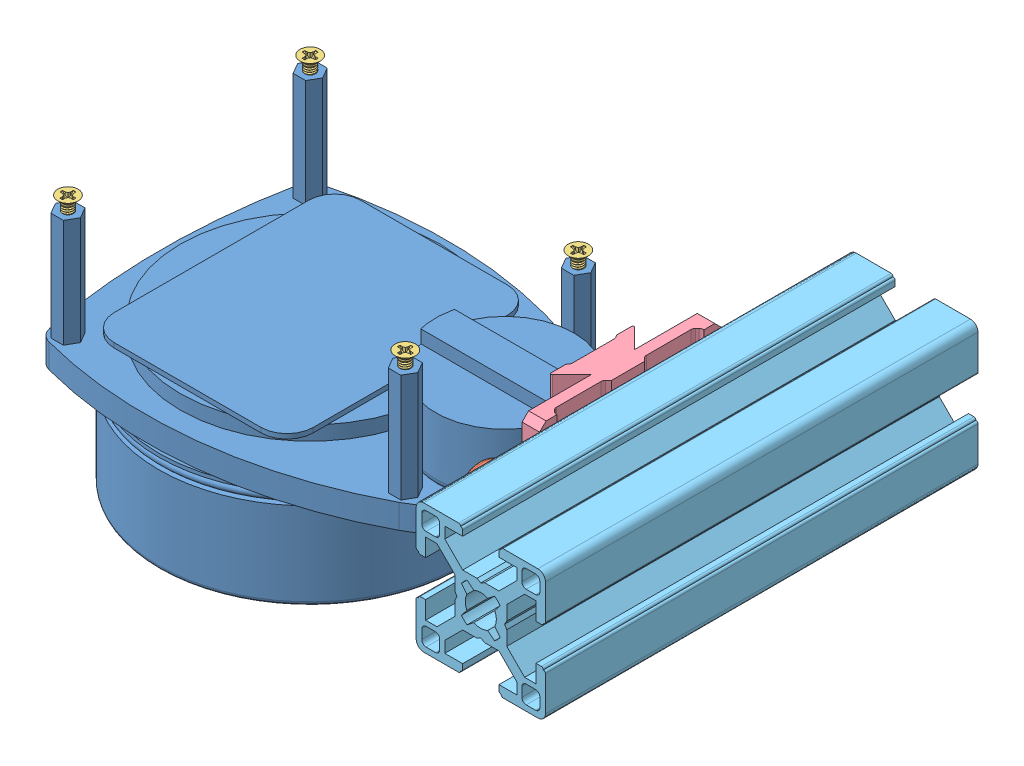
SolidWorks assembly LidarDoveTail, configuration Default. Lengths in mm.
Overall size (139.4 59.25 70).
10 component instances, 6 part files, 31 mates.
Components (placement in the parent):
- RPLidar_SCTL-1: RPLidar_SCTL [Default] at (-64 -20.75 0) x (1 0 0) z (0 0 -1) size (96.17 54.6 70)
- lidarBrack-1: lidarBrack [Default] at (-67.46 0 0) x (1 0 0) z (0 0 -1) (suppressed, hidden)
- screw M6x12 ph-1: screw M6x12 ph [95836A678] at (15.5 0 26) x (0 0 1) z (-1 0 0) size (12 12 18.26)
- screw M6x12 ph-2: screw M6x12 ph [95836A678] at (15.5 0 -26) x (0 0.920966 -0.389643) z (-1 0 0) size (12 12 18.26)
- screw m2.5x8 csink-1: screw m2.5x8 csink [91420A016] at (-92 11.95 -28) x (1 0 0) z (0 1 0) size (4.7 4.7 6.15)
- screw m2.5x8 csink-2: screw m2.5x8 csink [91420A016] at (-92 11.95 28) x (1 0 0) z (0 1 0) size (4.7 4.7 6.15)
- screw m2.5x8 csink-3: screw m2.5x8 csink [91420A016] at (-22 11.95 -20) x (1 0 0) z (0 1 0) size (4.7 4.7 6.15)
- screw m2.5x8 csink-4: screw m2.5x8 csink [91420A016] at (-22 11.95 20) x (1 0 0) z (0 1 0) size (4.7 4.7 6.15)
- twistBracket V3b-1: twistBracket V3b [Default] at (9.5 0 0) x (0 1 0) z (0 0 1) size (30 17.2 42)
- Extruded 3030 - Texas-1: Extruded 3030 - Texas [Default] at (25.45 0 0) size (29.9 29.9 60)
Mates (geometry in assembly coordinates):
- Coincident1: coordinate: point of lidarMount-1
- Parallel1: parallel anti-aligned: plane of RPLidar_SCTL-1 through (-64 -20.75 0) normal (0 -1 0)
- Coincident2: coincident anti-aligned: plane of RPLidar_SCTL-1 through (-64 -20.75 0) normal (0 0 -1)
- Coincident3: coincident anti-aligned: plane of RPLidar_SCTL-1 through (-64 10.35 0) normal (0 1 0); plane of lidarBrack-1 through (-97 10.35 -34) normal (0 -1 0)
- Coincident4: coincident anti-aligned: plane of lidarBrack-1 through (0 10.35 -34) normal (-1 0 0)
- Coincident5: coincident anti-aligned: plane of lidarBrack-1 through (-67.46 0 0) normal (0 0 -1)
- Concentric1: concentric anti-aligned: line of RPLidar_SCTL-1 through (-22 -18.75 -20) axis (0 -1 0); cylinder of lidarBrack-1 through (-22 -15 -20) axis (0 1 0) radius 1.4
- Concentric2: concentric anti-aligned: cylinder of lidarBrack-1 through (11.3 0 26) axis (-1 0 0) radius 3.15; cylinder of screw M6x12 ph-1 through (15.5 0 26) axis (1 0 0) radius 6
- Coincident6: coincident anti-aligned: plane of lidarBrack-1 through (4 0 26) normal (-1 0 0); plane of screw M6x12 ph-1 through (2 0 26) normal (1 0 0)
- Concentric3: concentric aligned: cylinder of lidarBrack-1 through (-3 0 -26) axis (1 0 0) radius 6.5; cylinder of screw M6x12 ph-2 through (15.5 0 -26) axis (1 0 0) radius 6
- Coincident7: coincident anti-aligned: plane of lidarBrack-1 through (4 0 -26) normal (-1 0 0); plane of screw M6x12 ph-2 through (2 0 -26) normal (1 0 0)
- Parallel2: parallel anti-aligned: plane of screw m2.5x8 csink-1 through (-92 11.95 -28) normal (0 0 -1)
- Concentric4: concentric anti-aligned: cylinder of lidarBrack-1 through (-92 -15 -28) axis (0 1 0) radius 1.4; line of screw m2.5x8 csink-1 through (-92 15.2018 -28) axis (0 -1 0)
- Parallel3: parallel anti-aligned: plane of screw m2.5x8 csink-2 through (-92 11.95 28) normal (0 0 -1)
- Concentric6: concentric anti-aligned: cylinder of lidarBrack-1 through (-92 -15 28) axis (0 1 0) radius 1.4; line of screw m2.5x8 csink-2 through (-92 15.2018 28) axis (0 -1 0)
- Parallel4: parallel anti-aligned: plane of screw m2.5x8 csink-3 through (-22 11.95 -20) normal (0 0 -1)
- Concentric7: concentric anti-aligned: cylinder of lidarBrack-1 through (-22 -15 -20) axis (0 1 0) radius 1.4; line of screw m2.5x8 csink-3 through (-22 15.2018 -20) axis (0 -1 0)
- Parallel5: parallel anti-aligned: plane of screw m2.5x8 csink-4 through (-22 11.95 20) normal (0 0 -1)
- Concentric8: concentric anti-aligned: cylinder of lidarBrack-1 through (-22 -15 20) axis (0 1 0) radius 1.4; line of screw m2.5x8 csink-4 through (-22 15.2018 20) axis (0 -1 0)
- Coincident13: coincident anti-aligned: plane of lidarBrack-1 through (-67.46 -10 0) normal (0 1 0); plane of twistBracket V3b-1 through (9.5 -10 0) normal (0 -1 0)
- Coincident14: coincident aligned: plane of twistBracket V3b-1 through (9.5 0 0) normal (0 1 0)
- Coincident15: coincident aligned: plane of twistBracket V3b-1 through (9.5 0 0) normal (0 0 1)
- Coincident16: coincident anti-aligned: plane of lidarBrack-1 through (6 15 -34) normal (1 0 0); plane of twistBracket V3b-1 through (6 -15 21) normal (-1 0 0)
- Coincident17: coincident aligned: plane of Extruded 3030 - Texas-1 through (25.45 0 0) normal (0 1 0)
- Coincident18: coincident aligned: plane of Extruded 3030 - Texas-1 through (25.45 0 0) normal (0 0 1)
- Coincident19: coincident anti-aligned: plane of lidarBrack-1 through (10.5 28.7568 34) normal (1 0 0); plane of Extruded 3030 - Texas-1 through (10.5 -5.15 -30) normal (-1 0 0)
- Parallel6: parallel aligned: plane of screw M6x12 ph-1 through (15.5 0 26) normal (0 1 0)
- Coincident20: coincident aligned: cone of lidarBrack-1 through (-92 12.5 -28) axis (0 -1 0); circle of screw m2.5x8 csink-1
- Coincident21: coincident aligned: cone of lidarBrack-1 through (-92 12.5 28) axis (0 -1 0); circle of screw m2.5x8 csink-2
- Coincident22: coincident aligned: cone of lidarBrack-1 through (-22 12.5 -20) axis (0 -1 0); circle of screw m2.5x8 csink-3
- Coincident23: coincident aligned: cone of lidarBrack-1 through (-22 12.5 20) axis (0 -1 0); circle of screw m2.5x8 csink-4
